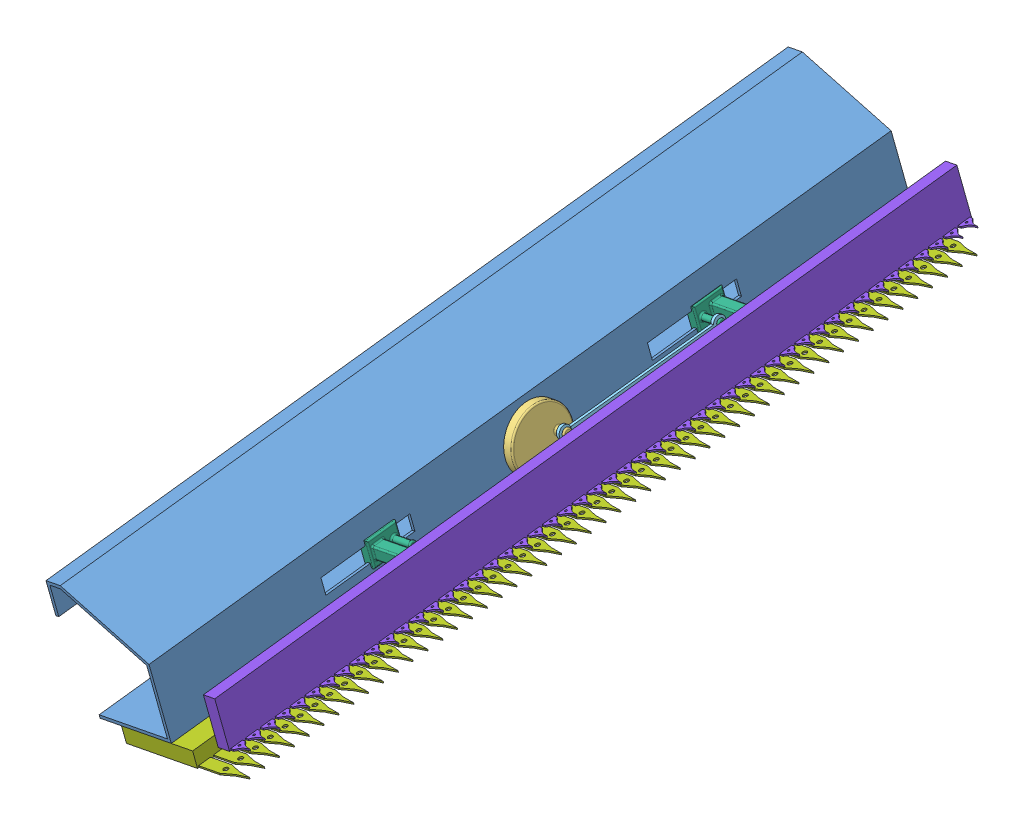
SolidWorks assembly harvestor, configuration Default. Lengths in mm.
Overall size (154.76 150.77 514.67).
9 component instances, 8 part files, 21 mates.
Components (placement in the parent):
- bumper-1: bumper [Default] at (449.4288 606.2861 262.0249) x (0.977312 0.210223 0.025824) z (0 -0.121924 0.992539) size (61.96 75 500)
- DC_harvester-1: DC_harvester [Default] at (419.3773 554.1072 507.4943) x (0 0.121924 -0.992539) z (-0.977312 -0.210223 -0.025824) size (37 37 101.8)
- rotator-1: rotator [Default] at (456.825 555.0533 507.6106) x (0.211803 -0.969936 -0.119847) z (0.977312 0.210223 0.025824) size (40 40 23)
- DCclamp harvestor-1: DCclamp harvestor [Default] at (424.7782 527.1161 522.8178) x (-0.977312 -0.210223 -0.025824) z (0 0.121924 -0.992539) size (22.5 39 37)
- oscillator part1-1: oscillator part1 [Default] at (467.5739 558.5917 497.9701) x (-0.001034 -0.117189 0.993109) z (-0.977312 -0.210223 -0.025824) size (111.87 8 2)
- oscillating slider-1: oscillating slider [Default] at (453.2171 569.6039 378.55) x (-0.977312 -0.210223 -0.025824) z (0 -0.121924 0.992539) size (26 16 20)
- oscillating slider-2: oscillating slider [Default] at (453.2171 540.3421 616.7595) x (-0.977312 -0.210223 -0.025824) z (0 0.121924 -0.992539) size (26 16 20)
- cutter part2-1: cutter part2 [Default] at (450.2458 494.7208 752.0784) x (-0.977312 -0.210223 -0.025824) z (0 0.121924 -0.992539) size (81.67 10 500)
- cutter part1-1: cutter part1 [Default] at (481.6166 581.9149 249.0851) x (0.211803 -0.970021 -0.119158) z (0 -0.121924 0.992539) size (30 17.63 500)
Mates (geometry in assembly coordinates):
- Concentric2: concentric: cylinder of DC_harvester-1 through (456.825 555.0533 507.6106) axis (-0.977312 -0.210223 -0.025824) radius 3; cylinder of rotator-1 through (447.0518 552.951 507.3523) axis (0.977312 0.210223 0.025824) radius 3
- Coincident4: coincident: plane of DC_harvester-1 through (456.825 555.0533 507.6106) normal (0.977312 0.210223 0.025824); plane of rotator-1 through (456.825 555.0533 507.6106) normal (-0.977312 -0.210223 -0.025824)
- Concentric3: concentric: cylinder of bumper-1 through (393.5327 541.4389 505.9382) axis (0.977312 0.210223 0.025824) radius 12.5; cylinder of DCclamp harvestor-1 through (430.633 549.4193 506.9185) axis (-0.977312 -0.210223 -0.025824) radius 13.8601
- Parallel3: parallel: plane of bumper-1 through (456.5817 503.1927 753.1191) normal (-0.211803 0.970021 0.119158); plane of DCclamp harvestor-1 through (426.1791 529.8975 485.8813) normal (0.211803 -0.970021 -0.119158)
- Concentric4: concentric: cylinder of DC_harvester-1 through (427.5056 548.7466 506.8358) axis (-0.977312 -0.210223 -0.025824) radius 6; cylinder of DCclamp harvestor-1 through (430.633 549.4193 506.9185) axis (-0.977312 -0.210223 -0.025824) radius 13.8601
- Distance1: distance = 30 mm: plane of bumper-1 through (447.7188 543.7835 758.1053) normal (-0.977312 -0.210223 -0.025824); plane of DCclamp harvestor-1 through (418.8961 567.9385 490.5543) normal (0.977312 0.210223 0.025824)
- Coincident8: coincident: plane of DC_harvester-1 through (419.3773 554.1072 507.4943) normal (0.977312 0.210223 0.025824); plane of DCclamp harvestor-1 through (424.7782 531.6273 486.0938) normal (-0.977312 -0.210223 -0.025824)
- Concentric5: concentric: cylinder of rotator-1 through (469.5286 559.0121 498.0217) axis (-0.977312 -0.210223 -0.025824) radius 2; cylinder of oscillator part1-1 through (465.6193 558.1712 497.9184) axis (0.977312 0.210223 0.025824) radius 2
- Distance2: distance = 3 mm: plane of oscillator part1-1 through (465.6193 558.1712 497.9184) normal (-0.977312 -0.210223 -0.025824); plane of rotator-1 through (462.6888 556.3146 507.7655) normal (0.977312 0.210223 0.025824)
- Concentric7: concentric: cylinder of oscillator part1-1 through (465.7267 570.344 394.7612) axis (0.977312 0.210223 0.025824) radius 2; cylinder of oscillating slider-1 through (469.3427 571.1218 394.8567) axis (-0.977312 -0.210223 -0.025824) radius 2
- Coincident12: coincident: plane of bumper-1 through (447.7188 543.7835 758.1053) normal (-0.977312 -0.210223 -0.025824); plane of oscillating slider-1 through (452.2398 566.9552 398.375) normal (0.977312 0.210223 0.025824)
- Coincident13: coincident: line of bumper-1 through (453.2988 558.463 427.4281) axis (0 0.121924 -0.992539); line of oscillating slider-1 through (453.2988 562.1051 397.7792) axis (0 0.121924 -0.992539)
- Width1: width: plane of bumper-1 through (453.2988 565.7785 367.8757) normal (0 -0.121924 0.992539); plane of bumper-1 through (453.2988 558.463 427.4281) normal (0 0.121924 -0.992539); plane of oscillating slider-1 through (453.2171 569.6039 378.55) normal (0 0.121924 -0.992539); plane of oscillating slider-1 through (453.2171 567.1654 398.4008) normal (0 -0.121924 0.992539)
- Coincident16: coincident: line of bumper-1 through (455.2534 532.0601 645.8384) axis (0 0.121924 -0.992539); line of oscillating slider-2 through (455.2534 538.1407 596.3387) axis (0 -0.121924 0.992539)
- Distance4: distance = 220 mm: plane of oscillating slider-2 through (476.5425 542.5164 606.9514) normal (0 0.121924 -0.992539); plane of oscillating slider-1 through (474.8481 577.0999 389.546) normal (0 -0.121924 0.992539)
- Coincident17: coincident: plane of bumper-1 through (458.96 501.6731 752.9325) normal (0.211803 -0.970021 -0.119158); plane of cutter part2-1 through (473.6196 506.0457 743.3944) normal (-0.211803 0.970021 0.119158)
- Distance5: distance = 15 mm: plane of cutter part2-1 through (475.7377 496.3455 742.2029) normal (0.977312 0.210223 0.025824); plane of bumper-1 through (449.4288 545.3241 758.2946) normal (0.977312 0.210223 0.025824)
- Coincident19: coincident: plane of bumper-1 through (449.4288 545.3241 758.2946) normal (0 -0.121924 0.992539); plane of cutter part2-1 through (450.2458 494.7208 752.0784) normal (0 -0.121924 0.992539)
- Coincident20: coincident: plane of oscillating slider-2 through (475.6953 545.1772 617.3534) normal (0.977312 0.210223 0.025824); plane of cutter part1-1 through (474.5304 594.405 260.6946) normal (-0.977312 -0.210223 -0.025824)
- Width2: width: plane of oscillating slider-2 through (476.5425 541.541 614.8917) normal (0 -0.121924 0.992539); plane of oscillating slider-1 through (474.8481 578.0753 381.6057) normal (0 0.121924 -0.992539); plane of cutter part1-1 through (481.6166 581.9149 249.0851) normal (0 0.121924 -0.992539); plane of cutter part1-1 through (481.6166 520.9528 745.3548) normal (0 -0.121924 0.992539)
- Distance6: distance = 8 mm: plane of cutter part2-1 through (475.7377 496.3455 742.2029) normal (0.211803 -0.970021 -0.119158); plane of cutter part1-1 through (480.8844 565.3044 257.1199) normal (0.211803 -0.970021 -0.119158)
